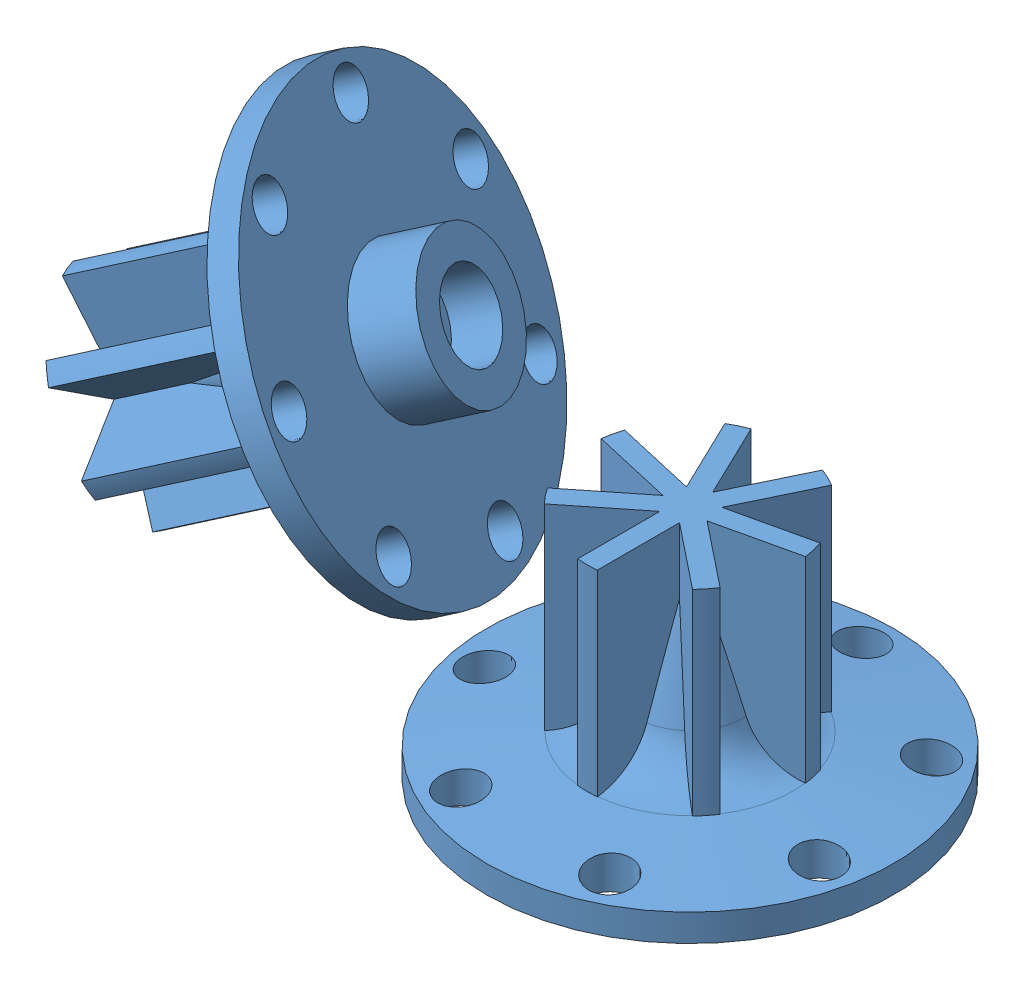
SolidWorks assembly Assem3, configuration Default. Lengths in mm.
Overall size (97.31 57.91 61.56).
2 component instances, 1 part files, 5 mates.
Components (placement in the parent):
- preferenceV2_dispenser_feedingDisk_withAgitator-1: preferenceV2_dispenser_feedingDisk_withAgitator [Default] at (-69.514 -8.8355 37.9286) size (41.5 30 41.5)
- preferenceV2_dispenser_feedingDisk_withAgitator-2: preferenceV2_dispenser_feedingDisk_withAgitator [Default] at (-111.5353 1.9749 27.5062) x (-0.326529 0.867337 0.375641) z (0.466135 -0.197964 0.862281) size (41.5 30 41.5)
Mates (geometry in assembly coordinates):
- Tangent2: tangent: plane of preferenceV2_dispenser_feedingDisk_withAgitator-1 through (-69.514 -16.8355 37.9286) normal (0 -1 0); circle of preferenceV2_dispenser_feedingDisk_withAgitator-2
- Tangent3: tangent: circle of preferenceV2_dispenser_feedingDisk_withAgitator-1; plane of preferenceV2_dispenser_feedingDisk_withAgitator-2
- Tangent4: tangent: plane of preferenceV2_dispenser_feedingDisk_withAgitator-1 through (-69.514 -16.8355 37.9286) normal (0 -1 0); circle of preferenceV2_dispenser_feedingDisk_withAgitator-2
- Coincident5: coincident: plane of preferenceV2_dispenser_feedingDisk_withAgitator-1 through (-69.514 -16.8355 37.9286) normal (0 -1 0); point of preferenceV2_dispenser_feedingDisk_withAgitator-2
- Coincident6: coincident: plane of preferenceV2_dispenser_feedingDisk_withAgitator-1 through (-69.514 -16.8355 37.9286) normal (0 -1 0); point of preferenceV2_dispenser_feedingDisk_withAgitator-2
